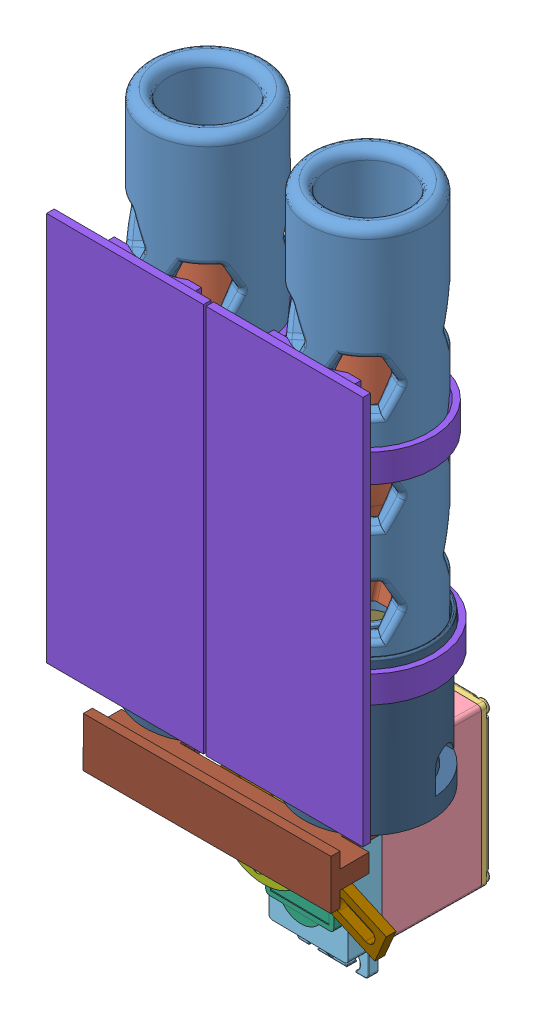
SolidWorks assembly MS-SA-0012h 1 in diameter Tube 2x, configuration Default. Lengths in mm.
Overall size (83.14 213.11 69.64).
20 component instances, 13 part files, 11 mates.
Components (placement in the parent):
- MS-P-0076 1 in diameter launcher tube-1: MS-P-0076 1 in diameter launcher tube [Default] at origin size (30.48 101.6 30.48)
- MS-P-0098 1.05 Dia flush version - Jordan 2-1: MS-P-0098 1.05 Dia flush version - Jordan 2 [Default] at (-0.0204 42.3918 -0.1144) x (0 1 0) z (0 0 1) size (122.24 19.3 19.3)
- MS-SA-0012j Torpedo Servo Assembly-1: MS-SA-0012j Torpedo Servo Assembly [Default] at (54.1619 -113.7236 34.1932) x (0.011892 0 -0.999929) z (0 1 0) size (48.58 29.09 55.5) (flexible)
  - Hitec HS-646WP-1: Hitec HS-646WP [Default] at (71.9223 31.717 49.4945) x (0 1 0) z (0 0 1) size (21 45.43 55.5)
    - 11886_bottom-1: 11886_bottom [Default] at (2.2223 -4.2785 0.9275) size (21 2.43 41.5)
    - 11886_middle-1: 11886_middle [Default] at (2.2223 -1.8785 0.9275) size (21 25.7 42.9)
    - 11886_upper-1: 11886_upper [Default] at (6.1473 23.8215 -5.3225) size (21 8.72 55.5)
    - 11886_top-1: 11886_top [Default] at (2.2223 32.5215 0.7275) size (20 8.6 36.5)
  - MS-C-0027-Servo Horn-1: MS-C-0027-Servo Horn [Default] at (34.0008 33.9393 61.172) x (0 0.158211 -0.987405) z (0 0.987405 0.158211) size (25.39 6.35 25.39)
  - MS-P-0110 Servo Holder-1: MS-P-0110 Servo Holder [Default] at (40.4008 45.327 142.2984) x (0 0.462192 0.88678) z (1 0 0) size (58.32 25.24 10) (hidden)
- MS-P-0108 Torpedo Mechanism Mount-2: MS-P-0108 Torpedo Mechanism Mount [Default] at (0.0503 -1.3928 -15.8837) x (0.003165 0 -0.999995) z (0.999995 0 0.003165) size (39.94 101.76 41.15)
- MS-P-0110 Servo Holder-1: MS-P-0110 Servo Holder [Default] at (54.8447 -12.5976 -6.4023) x (0 -1 0) z (0.011892 0 -0.999929) size (58.32 25.24 10) (hidden)
- MS-P-0108 Torpedo Mechanism Mount-4: MS-P-0108 Torpedo Mechanism Mount [Default] at (41.9196 -1.4091 -15.7133) x (0.003165 0 -0.999995) z (0.999995 0 0.003165) size (39.94 101.76 41.15)
- MS-P-0076 1 in diameter launcher tube-3: MS-P-0076 1 in diameter launcher tube [Default] at (41.8696 0.003 0.0743) size (30.48 101.6 30.48)
- MS-P-0098 1.05 Dia flush version - Jordan 2-3: MS-P-0098 1.05 Dia flush version - Jordan 2 [Default] at (41.9258 42.3948 0.8606) x (0 1 0) z (0 0 1) size (122.24 19.3 19.3)
- MS-P-0109 Torpedo Launching Axle-5: MS-P-0109 Torpedo Launching Axle [Default] at (116.4411 -59.1771 9.8213) x (0.396 0.918238 0.004709) z (0.011892 0 -0.999929) size (7.68 46.76 2.54) (hidden)
- MS-P-0105 Hook Pivot Holder-1: MS-P-0105 Hook Pivot Holder [Default] at (41.8696 -14.997 0.0743) size (33 40 33)
- MS-P-0105 Hook Pivot Holder-2: MS-P-0105 Hook Pivot Holder [Default] at (0 -15 0) size (33 40 33)
- MS-P-0111 String Routing Mechanism-1: MS-P-0111 String Routing Mechanism [Default] at (53.2108 -42.1944 6.7501) x (-0.99999 0.003165 0.003165) z (-0.003165 -0.999995 0.00001) size (64.54 20.01 12.98)
- MS-P-0104 String Hook-1: MS-P-0104 String Hook [Default] at (-1.9853 4.7014 17.8878) x (0 -1 0) z (0 0 1) size (42.19 3.9 52.37)
Mates (geometry in assembly coordinates):
- Coincident5: coincident anti-aligned: plane of MS-SA-0012j Torpedo Servo Assembly-1/Hitec HS-646WP-1/11886_upper-1 through (20.5455 -63.3016 -9.9705) normal (-0.999929 0 -0.011892); plane of MS-P-0110 Servo Holder-1 through (20.4767 -35.5176 -4.1909) normal (0.999929 0 0.011892)
- Coincident6: coincident anti-aligned: plane of MS-SA-0012j Torpedo Servo Assembly-1/Hitec HS-646WP-1/11886_upper-1 through (37.872 -91.0516 -11.6046) normal (-0.011892 0 0.999929); plane of MS-P-0110 Servo Holder-1 through (54.9042 -12.5976 -11.402) normal (0.011892 0 -0.999929)
- Coincident7: coincident anti-aligned: plane of MS-SA-0012j Torpedo Servo Assembly-1/Hitec HS-646WP-1/11886_upper-1 through (10.1943 -84.0516 -5.7333) normal (0 -1 0); plane of MS-P-0110 Servo Holder-1 through (10.1491 -84.0516 -1.9335) normal (0 1 0)
- Coincident8: coincident anti-aligned: plane of MS-SA-0012j Torpedo Servo Assembly-1/MS-C-0027-Servo Horn-1 through (20.5539 -52.5516 6.1408) normal (-0.011892 0 0.999929); plane of MS-P-0109 Torpedo Launching Axle-5 through (116.4713 -59.1771 7.2815) normal (0.011892 0 -0.999929)
- Concentric7: concentric aligned: circle of MS-SA-0012j Torpedo Servo Assembly-1/MS-C-0027-Servo Horn-1; circle of MS-P-0109 Torpedo Launching Axle-5
- Coincident9: coincident anti-aligned: plane of MS-P-0076 1 in diameter launcher tube-1 through (0 0 0) normal (0 -1 0); plane of MS-P-0105 Hook Pivot Holder-2 through (0 0 0) normal (0 1 0)
- Concentric8: concentric aligned: circle of MS-P-0076 1 in diameter launcher tube-1; circle of MS-P-0105 Hook Pivot Holder-2
- Coincident10: coincident anti-aligned: plane of MS-P-0076 1 in diameter launcher tube-3 through (41.8696 0.003 0.0743) normal (0 -1 0); plane of MS-P-0105 Hook Pivot Holder-1 through (41.8696 0.003 0.0743) normal (0 1 0)
- Concentric9: concentric aligned: circle of MS-P-0076 1 in diameter launcher tube-3; circle of MS-P-0105 Hook Pivot Holder-1
- Concentric10: concentric aligned: cylinder of MS-P-0076 1 in diameter launcher tube-1 through (0 101.6 0) axis (0 -1 0) radius 15.24; cylinder of MS-P-0108 Torpedo Mechanism Mount-2 through (0 52.3526 0) axis (0 -1 0) radius 15.715
- Concentric11: concentric anti-aligned: cylinder of MS-P-0108 Torpedo Mechanism Mount-4 through (41.8696 -4.2115 0.0743) axis (0 1 0) radius 16.75; cylinder of MS-P-0105 Hook Pivot Holder-1 through (41.8696 5.003 0.0743) axis (0 -1 0) radius 16.5
